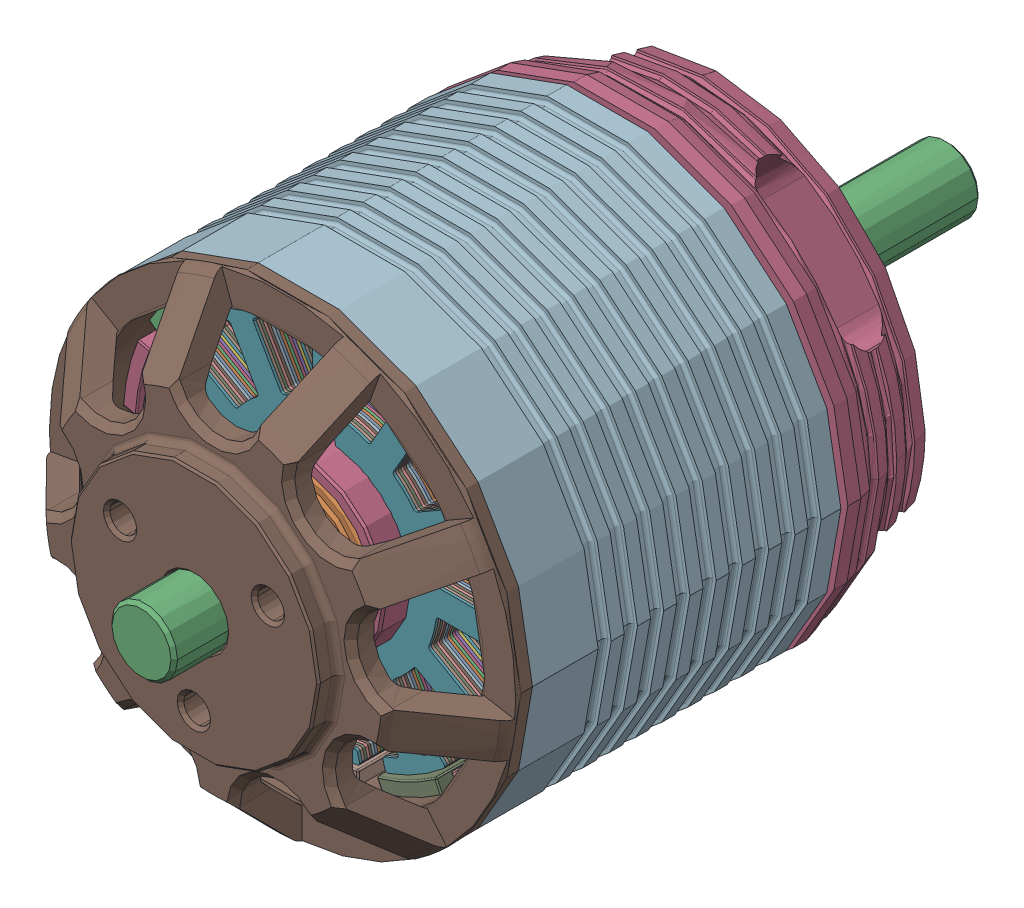
SolidWorks assembly BA-2820-Motor.STEP, configuration Default. Lengths in mm.
Overall size (35.63 35.67 61.5).
155 component instances, 14 part files, 0 mates.
Components (placement in the parent):
- 5x11x5-BRG.STEP-1: 5x11x5-BRG.STEP [Default] at (0.3814 18.4522 0.7645) x (0 0 -1) z (0.999739 0.022824 0) size (5 11 11)
  - 685HZZ_SOLID_1-1.STEP-1: 685HZZ_SOLID_1-1.STEP [Default] at origin size (5 6.35 6.35)
  - 685HZZ_SOLID_2-1.STEP-1: 685HZZ_SOLID_2-1.STEP [Default] at origin size (5 11 11)
  - 685HZZ_SOLID_3-1.STEP-1: 685HZZ_SOLID_3-1.STEP [Default] at origin size (2.94 9.96 10.15)
- 5x16x5-BRG.STEP-1: 5x16x5-BRG.STEP [Default] at (0.3814 18.4522 -25.7393) x (0 0 1) z (-0.999997 -0.00237 0) size (5 16 16)
  - 625HZZ_SOLID_1-1.STEP-1: 625HZZ_SOLID_1-1.STEP [Default] at origin size (5 8.86 8.86)
  - 625HZZ_SOLID_2-1.STEP-1: 625HZZ_SOLID_2-1.STEP [Default] at origin size (5 16 16)
  - 625HZZ_SOLID_3-1.STEP-1: 625HZZ_SOLID_3-1.STEP [Default] at origin size (2.94 12.54 12.7)
- 28x13x20mm-Stator.STEP-1: 28x13x20mm-Stator.STEP [Default] at (-11.9296 -7.8338 -48.7522) size (28 28 20)
  - 28x13x5mm-Stator.STEP-1: 28x13x5mm-Stator.STEP [Default] at (6.5198 12.3714 25.0893) size (28 28 5)
    - 28x13x1mm-Stator.STEP-1: 28x13x1mm-Stator.STEP [Default] at (34.0086 1.4103 18.4307) size (28 28 1)
      - 28x13-Stator Plate.STEP-1: 28x13-Stator Plate.STEP [Default] at (-28.2175 12.5042 6.2948) size (28 28 0.2)
      - 28x13-Stator Plate.STEP-2: 28x13-Stator Plate.STEP [Default] at (-28.2175 12.5042 6.0948) size (28 28 0.2)
      - 28x13-Stator Plate.STEP-3: 28x13-Stator Plate.STEP [Default] at (-28.2175 12.5042 5.8948) size (28 28 0.2)
      - 28x13-Stator Plate.STEP-4: 28x13-Stator Plate.STEP [Default] at (-28.2175 12.5042 5.6948) size (28 28 0.2)
      - 28x13-Stator Plate.STEP-5: 28x13-Stator Plate.STEP [Default] at (-28.2175 12.5042 5.4948) size (28 28 0.2)
    - 28x13x1mm-Stator.STEP-2: 28x13x1mm-Stator.STEP [Default] at (34.0086 1.4103 17.4307) size (28 28 1)
      - 28x13-Stator Plate.STEP-1: 28x13-Stator Plate.STEP [Default] at (-28.2175 12.5042 6.2948) size (28 28 0.2)
      - 28x13-Stator Plate.STEP-2: 28x13-Stator Plate.STEP [Default] at (-28.2175 12.5042 6.0948) size (28 28 0.2)
      - 28x13-Stator Plate.STEP-3: 28x13-Stator Plate.STEP [Default] at (-28.2175 12.5042 5.8948) size (28 28 0.2)
      - 28x13-Stator Plate.STEP-4: 28x13-Stator Plate.STEP [Default] at (-28.2175 12.5042 5.6948) size (28 28 0.2)
      - 28x13-Stator Plate.STEP-5: 28x13-Stator Plate.STEP [Default] at (-28.2175 12.5042 5.4948) size (28 28 0.2)
    - 28x13x1mm-Stator.STEP-3: 28x13x1mm-Stator.STEP [Default] at (34.0086 1.4103 16.4307) size (28 28 1)
      - 28x13-Stator Plate.STEP-1: 28x13-Stator Plate.STEP [Default] at (-28.2175 12.5042 6.2948) size (28 28 0.2)
      - 28x13-Stator Plate.STEP-2: 28x13-Stator Plate.STEP [Default] at (-28.2175 12.5042 6.0948) size (28 28 0.2)
      - 28x13-Stator Plate.STEP-3: 28x13-Stator Plate.STEP [Default] at (-28.2175 12.5042 5.8948) size (28 28 0.2)
      - 28x13-Stator Plate.STEP-4: 28x13-Stator Plate.STEP [Default] at (-28.2175 12.5042 5.6948) size (28 28 0.2)
      - 28x13-Stator Plate.STEP-5: 28x13-Stator Plate.STEP [Default] at (-28.2175 12.5042 5.4948) size (28 28 0.2)
    - 28x13x1mm-Stator.STEP-4: 28x13x1mm-Stator.STEP [Default] at (34.0086 1.4103 15.4307) size (28 28 1)
      - 28x13-Stator Plate.STEP-1: 28x13-Stator Plate.STEP [Default] at (-28.2175 12.5042 6.2948) size (28 28 0.2)
      - 28x13-Stator Plate.STEP-2: 28x13-Stator Plate.STEP [Default] at (-28.2175 12.5042 6.0948) size (28 28 0.2)
      - 28x13-Stator Plate.STEP-3: 28x13-Stator Plate.STEP [Default] at (-28.2175 12.5042 5.8948) size (28 28 0.2)
      - 28x13-Stator Plate.STEP-4: 28x13-Stator Plate.STEP [Default] at (-28.2175 12.5042 5.6948) size (28 28 0.2)
      - 28x13-Stator Plate.STEP-5: 28x13-Stator Plate.STEP [Default] at (-28.2175 12.5042 5.4948) size (28 28 0.2)
    - 28x13x1mm-Stator.STEP-5: 28x13x1mm-Stator.STEP [Default] at (34.0086 1.4103 14.4307) size (28 28 1)
      - 28x13-Stator Plate.STEP-1: 28x13-Stator Plate.STEP [Default] at (-28.2175 12.5042 6.2948) size (28 28 0.2)
      - 28x13-Stator Plate.STEP-2: 28x13-Stator Plate.STEP [Default] at (-28.2175 12.5042 6.0948) size (28 28 0.2)
      - 28x13-Stator Plate.STEP-3: 28x13-Stator Plate.STEP [Default] at (-28.2175 12.5042 5.8948) size (28 28 0.2)
      - 28x13-Stator Plate.STEP-4: 28x13-Stator Plate.STEP [Default] at (-28.2175 12.5042 5.6948) size (28 28 0.2)
      - 28x13-Stator Plate.STEP-5: 28x13-Stator Plate.STEP [Default] at (-28.2175 12.5042 5.4948) size (28 28 0.2)
  - 28x13x5mm-Stator.STEP-2: 28x13x5mm-Stator.STEP [Default] at (6.5198 12.3714 20.0893) size (28 28 5)
    - 28x13x1mm-Stator.STEP-1: 28x13x1mm-Stator.STEP [Default] at (34.0086 1.4103 18.4307) size (28 28 1)
      - 28x13-Stator Plate.STEP-1: 28x13-Stator Plate.STEP [Default] at (-28.2175 12.5042 6.2948) size (28 28 0.2)
      - 28x13-Stator Plate.STEP-2: 28x13-Stator Plate.STEP [Default] at (-28.2175 12.5042 6.0948) size (28 28 0.2)
      - 28x13-Stator Plate.STEP-3: 28x13-Stator Plate.STEP [Default] at (-28.2175 12.5042 5.8948) size (28 28 0.2)
      - 28x13-Stator Plate.STEP-4: 28x13-Stator Plate.STEP [Default] at (-28.2175 12.5042 5.6948) size (28 28 0.2)
      - 28x13-Stator Plate.STEP-5: 28x13-Stator Plate.STEP [Default] at (-28.2175 12.5042 5.4948) size (28 28 0.2)
    - 28x13x1mm-Stator.STEP-2: 28x13x1mm-Stator.STEP [Default] at (34.0086 1.4103 17.4307) size (28 28 1)
      - 28x13-Stator Plate.STEP-1: 28x13-Stator Plate.STEP [Default] at (-28.2175 12.5042 6.2948) size (28 28 0.2)
      - 28x13-Stator Plate.STEP-2: 28x13-Stator Plate.STEP [Default] at (-28.2175 12.5042 6.0948) size (28 28 0.2)
      - 28x13-Stator Plate.STEP-3: 28x13-Stator Plate.STEP [Default] at (-28.2175 12.5042 5.8948) size (28 28 0.2)
      - 28x13-Stator Plate.STEP-4: 28x13-Stator Plate.STEP [Default] at (-28.2175 12.5042 5.6948) size (28 28 0.2)
      - 28x13-Stator Plate.STEP-5: 28x13-Stator Plate.STEP [Default] at (-28.2175 12.5042 5.4948) size (28 28 0.2)
    - 28x13x1mm-Stator.STEP-3: 28x13x1mm-Stator.STEP [Default] at (34.0086 1.4103 16.4307) size (28 28 1)
      - 28x13-Stator Plate.STEP-1: 28x13-Stator Plate.STEP [Default] at (-28.2175 12.5042 6.2948) size (28 28 0.2)
      - 28x13-Stator Plate.STEP-2: 28x13-Stator Plate.STEP [Default] at (-28.2175 12.5042 6.0948) size (28 28 0.2)
      - 28x13-Stator Plate.STEP-3: 28x13-Stator Plate.STEP [Default] at (-28.2175 12.5042 5.8948) size (28 28 0.2)
      - 28x13-Stator Plate.STEP-4: 28x13-Stator Plate.STEP [Default] at (-28.2175 12.5042 5.6948) size (28 28 0.2)
      - 28x13-Stator Plate.STEP-5: 28x13-Stator Plate.STEP [Default] at (-28.2175 12.5042 5.4948) size (28 28 0.2)
    - 28x13x1mm-Stator.STEP-4: 28x13x1mm-Stator.STEP [Default] at (34.0086 1.4103 15.4307) size (28 28 1)
      - 28x13-Stator Plate.STEP-1: 28x13-Stator Plate.STEP [Default] at (-28.2175 12.5042 6.2948) size (28 28 0.2)
      - 28x13-Stator Plate.STEP-2: 28x13-Stator Plate.STEP [Default] at (-28.2175 12.5042 6.0948) size (28 28 0.2)
      - 28x13-Stator Plate.STEP-3: 28x13-Stator Plate.STEP [Default] at (-28.2175 12.5042 5.8948) size (28 28 0.2)
      - 28x13-Stator Plate.STEP-4: 28x13-Stator Plate.STEP [Default] at (-28.2175 12.5042 5.6948) size (28 28 0.2)
      - 28x13-Stator Plate.STEP-5: 28x13-Stator Plate.STEP [Default] at (-28.2175 12.5042 5.4948) size (28 28 0.2)
    - 28x13x1mm-Stator.STEP-5: 28x13x1mm-Stator.STEP [Default] at (34.0086 1.4103 14.4307) size (28 28 1)
      - 28x13-Stator Plate.STEP-1: 28x13-Stator Plate.STEP [Default] at (-28.2175 12.5042 6.2948) size (28 28 0.2)
      - 28x13-Stator Plate.STEP-2: 28x13-Stator Plate.STEP [Default] at (-28.2175 12.5042 6.0948) size (28 28 0.2)
      - 28x13-Stator Plate.STEP-3: 28x13-Stator Plate.STEP [Default] at (-28.2175 12.5042 5.8948) size (28 28 0.2)
      - 28x13-Stator Plate.STEP-4: 28x13-Stator Plate.STEP [Default] at (-28.2175 12.5042 5.6948) size (28 28 0.2)
      - 28x13-Stator Plate.STEP-5: 28x13-Stator Plate.STEP [Default] at (-28.2175 12.5042 5.4948) size (28 28 0.2)
  - 28x13x5mm-Stator.STEP-3: 28x13x5mm-Stator.STEP [Default] at (6.5198 12.3714 15.0893) size (28 28 5)
    - 28x13x1mm-Stator.STEP-1: 28x13x1mm-Stator.STEP [Default] at (34.0086 1.4103 18.4307) size (28 28 1)
      - 28x13-Stator Plate.STEP-1: 28x13-Stator Plate.STEP [Default] at (-28.2175 12.5042 6.2948) size (28 28 0.2)
      - 28x13-Stator Plate.STEP-2: 28x13-Stator Plate.STEP [Default] at (-28.2175 12.5042 6.0948) size (28 28 0.2)
      - 28x13-Stator Plate.STEP-3: 28x13-Stator Plate.STEP [Default] at (-28.2175 12.5042 5.8948) size (28 28 0.2)
      - 28x13-Stator Plate.STEP-4: 28x13-Stator Plate.STEP [Default] at (-28.2175 12.5042 5.6948) size (28 28 0.2)
      - 28x13-Stator Plate.STEP-5: 28x13-Stator Plate.STEP [Default] at (-28.2175 12.5042 5.4948) size (28 28 0.2)
    - 28x13x1mm-Stator.STEP-2: 28x13x1mm-Stator.STEP [Default] at (34.0086 1.4103 17.4307) size (28 28 1)
      - 28x13-Stator Plate.STEP-1: 28x13-Stator Plate.STEP [Default] at (-28.2175 12.5042 6.2948) size (28 28 0.2)
      - 28x13-Stator Plate.STEP-2: 28x13-Stator Plate.STEP [Default] at (-28.2175 12.5042 6.0948) size (28 28 0.2)
      - 28x13-Stator Plate.STEP-3: 28x13-Stator Plate.STEP [Default] at (-28.2175 12.5042 5.8948) size (28 28 0.2)
      - 28x13-Stator Plate.STEP-4: 28x13-Stator Plate.STEP [Default] at (-28.2175 12.5042 5.6948) size (28 28 0.2)
      - 28x13-Stator Plate.STEP-5: 28x13-Stator Plate.STEP [Default] at (-28.2175 12.5042 5.4948) size (28 28 0.2)
    - 28x13x1mm-Stator.STEP-3: 28x13x1mm-Stator.STEP [Default] at (34.0086 1.4103 16.4307) size (28 28 1)
      - 28x13-Stator Plate.STEP-1: 28x13-Stator Plate.STEP [Default] at (-28.2175 12.5042 6.2948) size (28 28 0.2)
      - 28x13-Stator Plate.STEP-2: 28x13-Stator Plate.STEP [Default] at (-28.2175 12.5042 6.0948) size (28 28 0.2)
      - 28x13-Stator Plate.STEP-3: 28x13-Stator Plate.STEP [Default] at (-28.2175 12.5042 5.8948) size (28 28 0.2)
      - 28x13-Stator Plate.STEP-4: 28x13-Stator Plate.STEP [Default] at (-28.2175 12.5042 5.6948) size (28 28 0.2)
      - 28x13-Stator Plate.STEP-5: 28x13-Stator Plate.STEP [Default] at (-28.2175 12.5042 5.4948) size (28 28 0.2)
    - 28x13x1mm-Stator.STEP-4: 28x13x1mm-Stator.STEP [Default] at (34.0086 1.4103 15.4307) size (28 28 1)
      - 28x13-Stator Plate.STEP-1: 28x13-Stator Plate.STEP [Default] at (-28.2175 12.5042 6.2948) size (28 28 0.2)
      - 28x13-Stator Plate.STEP-2: 28x13-Stator Plate.STEP [Default] at (-28.2175 12.5042 6.0948) size (28 28 0.2)
      - 28x13-Stator Plate.STEP-3: 28x13-Stator Plate.STEP [Default] at (-28.2175 12.5042 5.8948) size (28 28 0.2)
      - 28x13-Stator Plate.STEP-4: 28x13-Stator Plate.STEP [Default] at (-28.2175 12.5042 5.6948) size (28 28 0.2)
      - 28x13-Stator Plate.STEP-5: 28x13-Stator Plate.STEP [Default] at (-28.2175 12.5042 5.4948) size (28 28 0.2)
    - 28x13x1mm-Stator.STEP-5: 28x13x1mm-Stator.STEP [Default] at (34.0086 1.4103 14.4307) size (28 28 1)
      - 28x13-Stator Plate.STEP-1: 28x13-Stator Plate.STEP [Default] at (-28.2175 12.5042 6.2948) size (28 28 0.2)
      - 28x13-Stator Plate.STEP-2: 28x13-Stator Plate.STEP [Default] at (-28.2175 12.5042 6.0948) size (28 28 0.2)
      - 28x13-Stator Plate.STEP-3: 28x13-Stator Plate.STEP [Default] at (-28.2175 12.5042 5.8948) size (28 28 0.2)
      - 28x13-Stator Plate.STEP-4: 28x13-Stator Plate.STEP [Default] at (-28.2175 12.5042 5.6948) size (28 28 0.2)
      - 28x13-Stator Plate.STEP-5: 28x13-Stator Plate.STEP [Default] at (-28.2175 12.5042 5.4948) size (28 28 0.2)
  - 28x13x5mm-Stator.STEP-4: 28x13x5mm-Stator.STEP [Default] at (6.5198 12.3714 10.0893) size (28 28 5)
    - 28x13x1mm-Stator.STEP-1: 28x13x1mm-Stator.STEP [Default] at (34.0086 1.4103 18.4307) size (28 28 1)
      - 28x13-Stator Plate.STEP-1: 28x13-Stator Plate.STEP [Default] at (-28.2175 12.5042 6.2948) size (28 28 0.2)
      - 28x13-Stator Plate.STEP-2: 28x13-Stator Plate.STEP [Default] at (-28.2175 12.5042 6.0948) size (28 28 0.2)
      - 28x13-Stator Plate.STEP-3: 28x13-Stator Plate.STEP [Default] at (-28.2175 12.5042 5.8948) size (28 28 0.2)
      - 28x13-Stator Plate.STEP-4: 28x13-Stator Plate.STEP [Default] at (-28.2175 12.5042 5.6948) size (28 28 0.2)
      - 28x13-Stator Plate.STEP-5: 28x13-Stator Plate.STEP [Default] at (-28.2175 12.5042 5.4948) size (28 28 0.2)
    - 28x13x1mm-Stator.STEP-2: 28x13x1mm-Stator.STEP [Default] at (34.0086 1.4103 17.4307) size (28 28 1)
      - 28x13-Stator Plate.STEP-1: 28x13-Stator Plate.STEP [Default] at (-28.2175 12.5042 6.2948) size (28 28 0.2)
      - 28x13-Stator Plate.STEP-2: 28x13-Stator Plate.STEP [Default] at (-28.2175 12.5042 6.0948) size (28 28 0.2)
      - 28x13-Stator Plate.STEP-3: 28x13-Stator Plate.STEP [Default] at (-28.2175 12.5042 5.8948) size (28 28 0.2)
      - 28x13-Stator Plate.STEP-4: 28x13-Stator Plate.STEP [Default] at (-28.2175 12.5042 5.6948) size (28 28 0.2)
      - 28x13-Stator Plate.STEP-5: 28x13-Stator Plate.STEP [Default] at (-28.2175 12.5042 5.4948) size (28 28 0.2)
    - 28x13x1mm-Stator.STEP-3: 28x13x1mm-Stator.STEP [Default] at (34.0086 1.4103 16.4307) size (28 28 1)
      - 28x13-Stator Plate.STEP-1: 28x13-Stator Plate.STEP [Default] at (-28.2175 12.5042 6.2948) size (28 28 0.2)
      - 28x13-Stator Plate.STEP-2: 28x13-Stator Plate.STEP [Default] at (-28.2175 12.5042 6.0948) size (28 28 0.2)
      - 28x13-Stator Plate.STEP-3: 28x13-Stator Plate.STEP [Default] at (-28.2175 12.5042 5.8948) size (28 28 0.2)
      - 28x13-Stator Plate.STEP-4: 28x13-Stator Plate.STEP [Default] at (-28.2175 12.5042 5.6948) size (28 28 0.2)
      - 28x13-Stator Plate.STEP-5: 28x13-Stator Plate.STEP [Default] at (-28.2175 12.5042 5.4948) size (28 28 0.2)
    - 28x13x1mm-Stator.STEP-4: 28x13x1mm-Stator.STEP [Default] at (34.0086 1.4103 15.4307) size (28 28 1)
      - 28x13-Stator Plate.STEP-1: 28x13-Stator Plate.STEP [Default] at (-28.2175 12.5042 6.2948) size (28 28 0.2)
      - 28x13-Stator Plate.STEP-2: 28x13-Stator Plate.STEP [Default] at (-28.2175 12.5042 6.0948) size (28 28 0.2)
      - 28x13-Stator Plate.STEP-3: 28x13-Stator Plate.STEP [Default] at (-28.2175 12.5042 5.8948) size (28 28 0.2)
      - 28x13-Stator Plate.STEP-4: 28x13-Stator Plate.STEP [Default] at (-28.2175 12.5042 5.6948) size (28 28 0.2)
      - 28x13-Stator Plate.STEP-5: 28x13-Stator Plate.STEP [Default] at (-28.2175 12.5042 5.4948) size (28 28 0.2)
    - 28x13x1mm-Stator.STEP-5: 28x13x1mm-Stator.STEP [Default] at (34.0086 1.4103 14.4307) size (28 28 1)
      - 28x13-Stator Plate.STEP-1: 28x13-Stator Plate.STEP [Default] at (-28.2175 12.5042 6.2948) size (28 28 0.2)
      - 28x13-Stator Plate.STEP-2: 28x13-Stator Plate.STEP [Default] at (-28.2175 12.5042 6.0948) size (28 28 0.2)
      - 28x13-Stator Plate.STEP-3: 28x13-Stator Plate.STEP [Default] at (-28.2175 12.5042 5.8948) size (28 28 0.2)
      - 28x13-Stator Plate.STEP-4: 28x13-Stator Plate.STEP [Default] at (-28.2175 12.5042 5.6948) size (28 28 0.2)
      - 28x13-Stator Plate.STEP-5: 28x13-Stator Plate.STEP [Default] at (-28.2175 12.5042 5.4948) size (28 28 0.2)
- 2820-Rotor-Assem.STEP-1: 2820-Rotor-Assem.STEP [Default] at (-14.9395 1.0128 23.979) size (35.6 35.6 61.5)
  - 28mm-Endbell-9.STEP-1: 28mm-Endbell-9.STEP [Default] at (15.292 17.5059 -27.2126) size (35.6 35.6 14.5)
  - 2820-Fluxring.STEP-1: 2820-Fluxring.STEP [Default] at (15.292 17.5059 -44.2126) size (35.6 35.6 23.5)
  - 2820-Magnet.STEP-1: 2820-Magnet.STEP [Default] at (15.292 17.5059 -42.7126) size (5 2.2 20)
  - 2820-Magnet.STEP-2: 2820-Magnet.STEP [Default] at (15.292 17.5059 -42.7126) x (0.900969 0.433884 0) z (0 0 1) size (5 2.2 20)
  - 2820-Magnet.STEP-3: 2820-Magnet.STEP [Default] at (15.292 17.5059 -42.7126) x (0.62349 0.781831 0) z (0 0 1) size (5 2.2 20)
  - 2820-Magnet.STEP-4: 2820-Magnet.STEP [Default] at (15.292 17.5059 -42.7126) x (0.222521 0.974928 0) z (0 0 1) size (5 2.2 20)
  - 2820-Magnet.STEP-5: 2820-Magnet.STEP [Default] at (15.292 17.5059 -42.7126) x (-0.222521 0.974928 0) z (0 0 1) size (5 2.2 20)
  - 2820-Magnet.STEP-6: 2820-Magnet.STEP [Default] at (15.292 17.5059 -42.7126) x (-0.62349 0.781831 0) z (0 0 1) size (5 2.2 20)
  - 2820-Magnet.STEP-7: 2820-Magnet.STEP [Default] at (15.292 17.5059 -42.7126) x (-0.900969 0.433884 0) z (0 0 1) size (5 2.2 20)
  - 2820-Magnet.STEP-8: 2820-Magnet.STEP [Default] at (15.292 17.5059 -42.7126) x (-1 0 0) z (0 0 1) size (5 2.2 20)
  - 2820-Magnet.STEP-9: 2820-Magnet.STEP [Default] at (15.292 17.5059 -42.7126) x (-0.900969 -0.433884 0) z (0 0 1) size (5 2.2 20)
  - 2820-Magnet.STEP-10: 2820-Magnet.STEP [Default] at (15.292 17.5059 -42.7126) x (-0.62349 -0.781831 0) z (0 0 1) size (5 2.2 20)
  - 2820-Magnet.STEP-11: 2820-Magnet.STEP [Default] at (15.292 17.5059 -42.7126) x (-0.222521 -0.974928 0) z (0 0 1) size (5 2.2 20)
  - 2820-Magnet.STEP-12: 2820-Magnet.STEP [Default] at (15.292 17.5059 -42.7126) x (0.222521 -0.974928 0) z (0 0 1) size (5 2.2 20)
  - 2820-Magnet.STEP-13: 2820-Magnet.STEP [Default] at (15.292 17.5059 -42.7126) x (0.62349 -0.781831 0) z (0 0 1) size (5 2.2 20)
  - 2820-Magnet.STEP-14: 2820-Magnet.STEP [Default] at (15.292 17.5059 -42.7126) x (0.900969 -0.433884 0) z (0 0 1) size (5 2.2 20)
  - 2820-Shaft.STEP-1: 2820-Shaft.STEP [Default] at (15.292 17.5059 -70.2126) size (5 5 61.5)
- 2820-Mount.STEP-1: 2820-Mount.STEP [Default] at (0.3814 18.4522 -28.7374) size (35.6 35.6 32)
- Spacer-5mm.STEP-1: Spacer-5mm.STEP [Default] at (0.3525 18.5187 3.2664) size (7 7 0.5)
- Spacer-5mm.STEP-2: Spacer-5mm.STEP [Default] at (0.3525 18.5187 -28.7412) size (7 7 0.5)
- Collar-5mm.STEP-1: Collar-5mm.STEP [Default] at (0.3525 18.5187 -33.7412) x (0.028497 0.999594 0) z (0 0 1) size (11 11 5)
